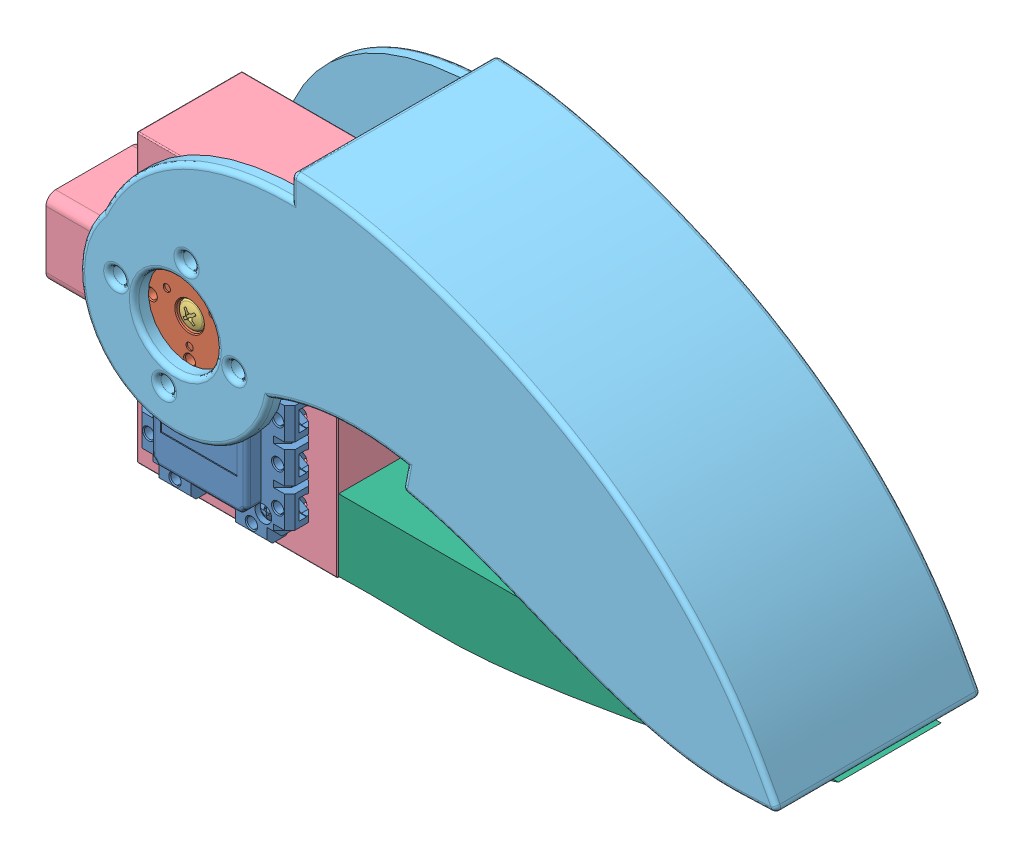
SolidWorks assembly Gripper_assembled, configuration Default. Lengths in mm.
Overall size (177.25 101.63 61.68).
7 component instances, 6 part files, 7 mates.
Components (placement in the parent):
- AX-12_18A-1-1: AX-12_18A-1 [Default] at (23.4576 40.9134 34.0008) size (32 50.04 40.32)
  - dynamixel_AXseries-1: dynamixel_AXseries [Default] at origin size (32 50.04 38.37)
  - AX12_horn-1: AX12_horn [Default] at (0 0 19.1) x (0 1 0) z (0 0 1) size (22 22 6.7)
  - BHS_M2_6X8-1: BHS_M2_6X8 [Default] at (0 0 19.55) x (0.628847 -0.777529 0) z (-0.777529 -0.628847 0) size (5.5 9.6 5.5)
- Gripper-1: Gripper [Default] at (-1.4424 28.9134 34.0008) x (1 0 0) z (0 -1 0) size (62 22 60)
- Gripper Top claw-1: Gripper Top claw [Default] at (23.4576 40.9134 18.0408) x (0 0 1) z (-0.982321 0.187207 0) size (61.68 75.14 148.57)
- Gripper bottom claw fixed-1: Gripper bottom claw fixed [Default] at (44.4576 14.1634 44.7508) size (104.6 15.83 21.5)
Mates (geometry in assembly coordinates):
- Coincident2: coincident anti-aligned: plane of AX-12_18A-1-1/dynamixel_AXseries-1 through (36.4576 52.4134 15.0008) normal (0 1 0); plane of Gripper-1 through (36.4576 52.4134 9.0008) normal (0 -1 0)
- Coincident3: coincident anti-aligned: plane of AX-12_18A-1-1/dynamixel_AXseries-1 through (36.4576 5.4134 15.0008) normal (1 0 0); plane of Gripper-1 through (36.4576 5.4134 9.0008) normal (-1 0 0)
- Coincident4: coincident anti-aligned: plane of AX-12_18A-1-1/dynamixel_AXseries-1 through (23.4576 40.9134 45.0008) normal (0 0 -1); plane of Gripper-1 through (44.4576 58.9134 45.0008) normal (0 0 1)
- Coincident18: coincident anti-aligned: plane of AX-12_18A-1-1/AX12_horn-1 through (23.4576 40.9134 54.9408) normal (0 0 1); plane of Gripper Top claw-1 through (23.4576 40.9134 54.9408) normal (0 0 -1)
- Concentric9: concentric anti-aligned: cylinder of AX-12_18A-1-1/dynamixel_AXseries-1 through (23.4576 40.9134 18.0008) axis (0 0 -1) radius 5.5; cylinder of Gripper Top claw-1 through (23.4576 40.9134 15.0408) axis (0 0 1) radius 8.6429
- Coincident19: coincident anti-aligned: line of Gripper bottom claw fixed-1 through (44.4576 -0.8366 23.2508) axis (0 0 1); line of Gripper-1 through (44.4576 -0.8366 44.7508) axis (0 0 -1)
- Coincident20: coincident aligned: line of Gripper-1 through (44.4576 58.6634 44.7508) axis (0 -1 0); line of Gripper bottom claw fixed-1 through (44.4576 14.1634 44.7508) axis (0 -1 0)
